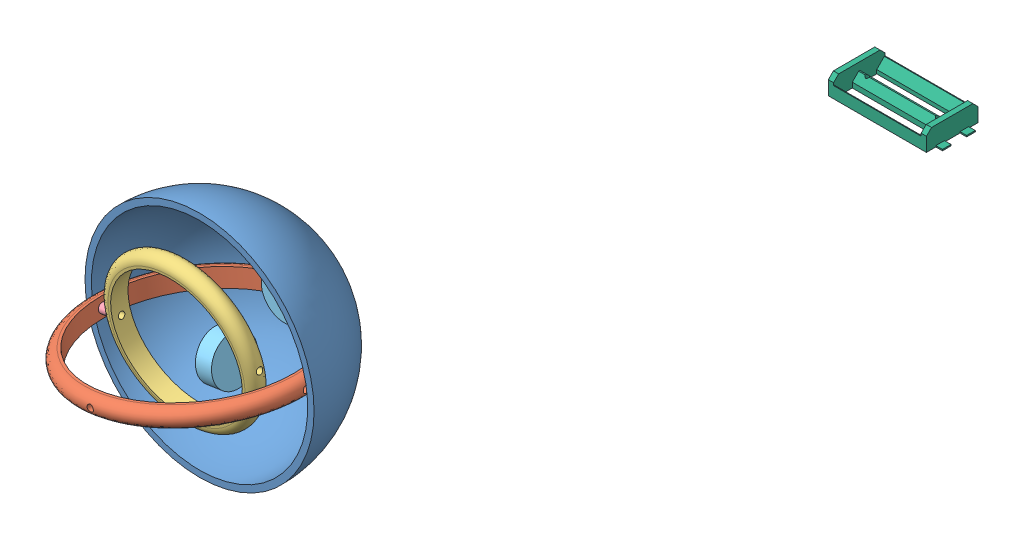
SolidWorks assembly Main, configuration Default. Lengths in mm.
Overall size (450.18 305.55 342.88).
7 component instances, 6 part files, 8 mates.
Components (placement in the parent):
- ShellHalf-1: ShellHalf [Default] at (78.6344 16.6054 0) size (180 180 89.97)
- RingX-1: RingX [Default] at (77.5842 113.5261 0.5002) x (0.150017 -0.988683 0) z (0 0 1) size (14 171.24 171.23)
- RingY-1: RingY [Default] at (67.7073 105.2944 -6.4488) x (0.01807 -0.119088 0.992719) z (0.988683 0.150017 0) size (14 119 119.2)
- Spacer-1: Spacer [Default] at (3.075 94.6347 0.5002) x (0.137178 -0.90407 -0.404771) z (0.988683 0.150017 0) size (7 7 6)
- 14HK Motor-1: 14HK Motor [Default] at (78.6343 106.6054 -66.5709) x (0.982808 0.184632 0) z (-0.184632 0.982808 0) size (36 21.2 36)
- 14HK Motor-2: 14HK Motor [Default] at (106.7399 110.3642 0.5002) x (-0.052522 0.346146 0.936709) z (0.140523 -0.926109 0.350108) size (36 21.2 36)
- 18650 Battery Holder-1: 18650 Battery Holder [Default] at (275.8735 307.1529 104.2621) size (87.56 15 40.53)
Mates (geometry in assembly coordinates):
- Concentric1: concentric aligned: cylinder of ShellHalf-1 through (78.6344 106.6054 -90.001) axis (0 0 1) radius 2.5; cylinder of RingX-1 through (78.6343 106.6054 -85.0008) axis (0 0 1) radius 2.5
- Concentric2: concentric aligned: cylinder of RingX-1 through (-5.8241 93.2844 0.5002) axis (0.988683 0.150017 0) radius 2.5; cylinder of RingY-1 through (9.0061 95.5346 0.5002) axis (0.988683 0.150017 0) radius 2.5
- Tangent4: tangent: circle of ShellHalf-1; curve of RingX-1
- Concentric5: concentric anti-aligned: cylinder of RingY-1 through (9.0061 95.5346 0.5002) axis (0.988683 0.150017 0) radius 2.5; cylinder of Spacer-1 through (9.0071 95.5348 0.5002) axis (-0.988683 -0.150017 0) radius 2.5
- Tangent8: tangent aligned: cylinder of RingX-1 through (77.5842 113.5261 0.5002) axis (-0.150017 0.988683 0) radius 76.5; plane of Spacer-1 through (3.075 94.6347 0.5002) normal (-0.988683 -0.150017 0)
- Tangent9: tangent anti-aligned: torus of RingY-1; plane of Spacer-1 through (9.0071 95.5348 0.5002) normal (0.988683 0.150017 0)
- Concentric7: concentric aligned: cylinder of RingX-1 through (78.6343 106.6054 -85.0008) axis (0 0 1) radius 2.5; cylinder of 14HK Motor-1 through (78.6343 106.6054 -87.7709) axis (0 0 1) radius 2
- Concentric8: concentric aligned: cylinder of RingY-1 through (9.0061 95.5346 0.5002) axis (0.988683 0.150017 0) radius 2.5; cylinder of 14HK Motor-2 through (85.7799 107.1839 0.5002) axis (0.988683 0.150017 0) radius 2
